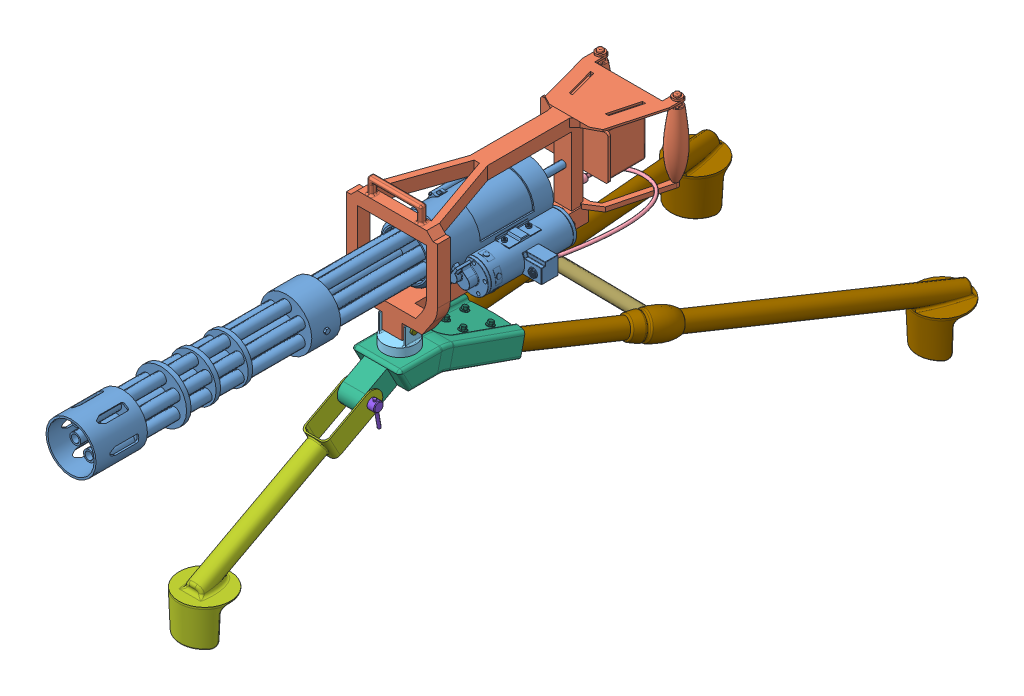
SolidWorks assembly Assembly, configuration Varsayılan. Lengths in mm.
Overall size (486.57 451.98 1218.93).
36 component instances, 16 part files, 68 mates.
Components (placement in the parent):
- MiniGun-1: MiniGun [Varsayılan] at (-74.6119 7.8433 313) size (160.38 103.95 766)
- 1-1: 1 [Varsayılan] at (-74.6119 19.0929 -136.8107) size (154.47 191.63 401.92)
- 4-1: 4 [Varsayılan] at (-65.4883 28.276 -402.319) x (-1 0 0) z (0 -0.026483 -0.999649) size (18.25 25 8)
- 5-1: 5 [Varsayılan] at (1.0631 1.0229 -8.0155) x (0.999813 -0.019344 0) z (0 0 1) size (114.19 21.33 191.94)
- 6-1: 6 [Varsayılan] at (-74.6119 -86.8456 -141.6319) size (50 96.35 50)
- 7-1: 7 [Varsayılan] at (-74.6119 -143.6696 -129.1319) x (0 0 1) z (-1 0 0) size (225.42 64.92 113.88)
- 8-1: 8 [Varsayılan] at (-74.6119 -174.7284 -49.3966) x (1 0 0) z (0 -0.470588 0.882353) size (81.78 67.4 354.56)
- 9-1: 9 [Varsayılan] at (-94.1119 -146.5519 -66.1025) x (0 0.163632 -0.986522) z (0 0.986522 0.163632) size (30 52 48)
- 10-1: 10 [Varsayılan] at (-39.5274 -147.0531 -249.291) x (-0.275637 0.214193 0.937094) z (-0.062166 -0.97679 0.204981) size (608.85 81.51 95.1)
- 10-2: 10 [Varsayılan] at (-109.6964 -147.0531 -249.291) x (0.275637 0.214193 0.937094) z (0.051454 -0.976749 0.208122) size (608.85 81.51 95.1)
- socket thin pilot cap screw_din-1: socket thin pilot cap screw_din [DIN 6912 - M4 x 10 --- 6.5N] at (-25.4764 1.646 -243) x (0 -1 0) z (-0.098825 0 0.995105) size (12.8 7 7)
- socket thin pilot cap screw_din-2: socket thin pilot cap screw_din [DIN 6912 - M4 x 10 --- 6.5N] at (-25.4764 1.6451 -281) x (0 -1 0) z (0 0 1) size (12.8 7 7)
- hexalobular socket cheese head_iso-3: hexalobular socket cheese head_iso [ISO 14580 - #4 x 5 x 3.6 - 4.8-N] at (-10.8119 -16.6334 -327) x (1 0 0) z (0 1 0) size (7 8.1 7)
- hexalobular socket cheese head_iso-5: hexalobular socket cheese head_iso [ISO 14580 - #4 x 5 x 3.6 - 4.8-N] at (-26.8628 -7.1408 -327) x (1 0 0) z (0 1 0) size (7 8.1 7)
- hexalobular socket cheese head_iso-7: hexalobular socket cheese head_iso [ISO 14580 - #4 x 5 x 3.6 - 4.8-N] at (-43.3074 -16.6352 -327) x (1 0 0) z (0 1 0) size (7 8.1 7)
- hexalobular socket cheese head_iso-9: hexalobular socket cheese head_iso [ISO 14580 - #4 x 5 x 3.6 - 4.8-N] at (-10.4181 -35.6239 -327) x (1 0 0) z (0 1 0) size (7 8.1 7)
- hexalobular socket cheese head_iso-10: hexalobular socket cheese head_iso [ISO 14580 - #4 x 5 x 3.6 - 4.8-N] at (-26.8628 -45.1182 -327) x (1 0 0) z (0 1 0) size (7 8.1 7)
- hexalobular socket cheese head_iso-11: hexalobular socket cheese head_iso [ISO 14580 - #4 x 5 x 3.6 - 4.8-N] at (-43.3074 -35.6239 -327) x (1 0 0) z (0 1 0) size (7 8.1 7)
- 11-1: 11 [Varsayılan] at (-5.6608 -84.396 1.2114) x (0.999924 -0.001016 0.012303) z (0.003781 0.97392 -0.226862) size (190.05 18 18)
- pan head cross recess screw_iso-2: pan head cross recess screw_iso [ISO 7045 - M1.6 x 5 - Z - 5N] at (16.5372 -20.1295 -280.3) x (0 0 1) z (-1 0 0) size (6.27 3.2 3.2)
- pan head cross recess screw_iso-3: pan head cross recess screw_iso [ISO 7045 - M1.6 x 5 - Z - 5N] at (6.5372 -20.1295 -280.3) x (0 0 1) z (-1 0 0) size (6.27 3.2 3.2)
- pan head cross recess screw_iso-4: pan head cross recess screw_iso [ISO 7045 - M1.6 x 5 - Z - 5N] at (16.5372 -30.1295 -280.3) x (0 0 1) z (-1 0 0) size (6.27 3.2 3.2)
- pan head cross recess screw_iso-5: pan head cross recess screw_iso [ISO 7045 - M1.6 x 5 - Z - 5N] at (6.5372 -30.1295 -280.3) x (0 0 1) z (-1 0 0) size (6.27 3.2 3.2)
- socket head cap screw_iso-2: socket head cap screw_iso [ISO 4762 M3 x 12 - 12N] at (-65.0857 13.3433 -337) x (0 0 1) z (-1 0 0) size (15 5.5 5.5)
- socket head cap screw_iso-3: socket head cap screw_iso [ISO 4762 M3 x 12 - 12N] at (-65.0857 2.3433 -337) x (0 0 1) z (-1 0 0) size (15 5.5 5.5)
- socket head cap screw_iso-4: socket head cap screw_iso [ISO 4762 M3 x 12 - 12N] at (-74.6119 -3.1567 -337) x (0 0 1) z (-1 0 0) size (15 5.5 5.5)
- socket head cap screw_iso-5: socket head cap screw_iso [ISO 4762 M3 x 12 - 12N] at (-74.6119 18.8433 -337) x (0 0 1) z (-1 0 0) size (15 5.5 5.5)
- socket head cap screw_iso-6: socket head cap screw_iso [ISO 4762 M3 x 12 - 12N] at (-84.1382 13.3433 -337) x (0 0 1) z (-1 0 0) size (15 5.5 5.5)
- socket head cap screw_iso-7: socket head cap screw_iso [ISO 4762 M3 x 12 - 12N] at (-84.1382 2.3433 -337) x (0 0 1) z (-1 0 0) size (15 5.5 5.5)
- hex flange bolt small_iso-1: hex flange bolt small_iso [ISO 4162 - M5 x 12 x 12-N] at (-61.23 -119.0865 -214.8986) x (0 -0.974859 0.222825) z (-0.222825 0.217223 0.950349) size (17.6 11.4 11.4)
- hex flange bolt small_iso-2: hex flange bolt small_iso [ISO 4162 - M5 x 12 x 12-N] at (-87.9939 -119.0865 -214.8986) x (0 -0.974859 0.222825) z (-0.222825 0.217223 0.950349) size (17.6 11.4 11.4)
- hex flange bolt small_iso-3: hex flange bolt small_iso [ISO 4162 - M5 x 12 x 12-N] at (-94.5826 -127.419 -251.3536) x (0 -0.974859 0.222825) z (-0.222825 0.217223 0.950349) size (17.6 11.4 11.4)
- hex flange bolt small_iso-4: hex flange bolt small_iso [ISO 4162 - M5 x 12 x 12-N] at (-54.6413 -127.419 -251.3536) x (0 -0.974859 0.222825) z (-0.222825 0.217223 0.950349) size (17.6 11.4 11.4)
- socket thin pilot cap screw_din-3: socket thin pilot cap screw_din [DIN 6912 - M4 x 10 --- 6.5N] at (-27.5222 -11.7662 -175.8158) x (-0.843846 0.536586 0) z (0.053028 0.083393 0.995105) size (12.8 7 7)
- socket thin pilot cap screw_din-4: socket thin pilot cap screw_din [DIN 6912 - M4 x 10 --- 6.5N] at (-39.8728 -31.189 -175.8158) x (-0.843846 0.536586 0) z (0.053028 0.083393 0.995105) size (12.8 7 7)
- 12-1: 12 [Varsayılan] at (-98.6119 -78.6696 -129.1319) size (48 15 15)
Mates (geometry in assembly coordinates):
- Çakışık1: coincident anti-aligned: plane of MiniGun-1 through (-74.6119 7.8433 -383) normal (0 0 -1); plane of 1-1 through (-60.9883 100.6283 -383) normal (0 0 1)
- Çakışık2: coincident anti-aligned: plane of MiniGun-1 through (-87.8188 -49 -166.5) normal (0 -1 0); plane of 1-1 through (-74.6119 -49 -116.8107) normal (0 1 0)
- Genişlik1: width anti-aligned: plane of MiniGun-1 through (-87.8188 -27.5086 -166.5) normal (-1 0 0); plane of MiniGun-1 through (-61.4051 -49 -166.5) normal (1 0 0); plane of 1-1 through (-58.826 -74.5262 -116.8107) normal (1 0 0); plane of 1-1 through (-90.3979 -74.5262 -116.8107) normal (-1 0 0)
- Çakışık12: coincident anti-aligned: plane of MiniGun-1 through (11.5372 -25.1295 -275.5) normal (0 0 -1); plane of 5-1 through (11.5372 -25.1295 -275.5) normal (0 0 1)
- Eş Merkezli1: concentric anti-aligned: cylinder of MiniGun-1 through (11.5372 -25.1295 -279.5) axis (0 0 1) radius 3.351; cylinder of 5-1 through (11.5372 -25.1295 -275.5) axis (0 0 -1) radius 3.3494
- Çakışık13: coincident anti-aligned: axis of 1-1 through (-90.3979 -78.6696 -129.1319) axis (1 0 0); axis of 6-1 through (-93.6119 -78.6696 -129.1319) axis (-1 0 0)
- Genişlik2: width anti-aligned: plane of 6-1 through (-55.6119 -96.6696 -116.6319) normal (-1 0 0); plane of 6-1 through (-93.6119 -96.6696 -116.6319) normal (1 0 0); plane of 1-1 through (-58.826 -74.5262 -116.8107) normal (1 0 0); plane of 1-1 through (-90.3979 -74.5262 -116.8107) normal (-1 0 0)
- Çakışık14: coincident anti-aligned: axis of 6-1 through (-74.6119 -108.6696 -129.1319) axis (0 1 0); axis of 7-1 through (-74.6119 -104.6696 -129.1319) axis (0 -1 0)
- Çakışık15: coincident anti-aligned: plane of 6-1 through (-74.6119 -103.6696 -129.1319) normal (0 -1 0); plane of 7-1 through (-74.6119 -103.6696 -129.1319) normal (0 1 0)
- Paralel1: parallel aligned: plane of 1-1 through (-74.6119 19.0929 -116.8107) normal (0 0 1); plane of 6-1 through (-74.6119 -86.8456 -116.6319) normal (0 0 1)
- Çakışık17: coincident aligned: axis of 7-1 through (-57.1119 -146.5519 -66.1025) axis (-1 0 0); axis of 8-1 through (-92.1119 -146.5519 -66.1025) axis (-1 0 0)
- Çakışık18: coincident anti-aligned: plane of 7-1 through (-57.1119 -139.5519 -43.1025) normal (1 0 0); plane of 8-1 through (-57.1119 -144.7284 -33.3966) normal (-1 0 0)
- Çakışık19: coincident aligned: axis of 7-1 through (-57.1119 -146.5519 -66.1025) axis (-1 0 0); axis of 9-1 through (-45.1119 -146.5519 -66.1025) axis (-1 0 0)
- Çakışık20: coincident anti-aligned: plane of 8-1 through (-94.1119 -144.7284 -33.3966) normal (-1 0 0); plane of 9-1 through (-94.1119 -146.5519 -66.1025) normal (1 0 0)
- Çakışık26: coincident aligned: plane of 7-1 through (-92.1119 -139.5519 -43.1025) normal (0 0.882353 0.470588); plane of 8-1 through (-74.6119 -144.7284 -33.3966) normal (0 0.882353 0.470588)
- Çakışık27: coincident anti-aligned: axis of 7-1 through (-39.5274 -147.0531 -249.291) axis (0.275637 -0.214193 -0.937094); axis of 10-1 through (4.5745 -181.324 -399.2261) axis (-0.275637 0.214193 0.937094)
- Çakışık28: coincident anti-aligned: plane of 7-1 through (-39.5274 -147.0531 -249.291) normal (0.275637 -0.214193 -0.937094); plane of 10-1 through (-39.5274 -147.0531 -249.291) normal (-0.275637 0.214193 0.937094)
- Çakışık29: coincident anti-aligned: axis of 7-1 through (-109.6964 -147.0531 -249.291) axis (-0.275637 -0.214193 -0.937094); axis of 10-2 through (-153.7984 -181.324 -399.2261) axis (0.275637 0.214193 0.937094)
- Çakışık30: coincident anti-aligned: plane of 7-1 through (-109.6964 -147.0531 -249.291) normal (-0.275637 -0.214193 -0.937094); plane of 10-2 through (-109.6964 -147.0531 -249.291) normal (0.275637 0.214193 0.937094)
- Paralel14: parallel aligned: plane of 1-1 through (-90.3979 -74.5262 -116.8107) normal (-1 0 0); plane of 7-1 through (-112.1119 -108.6696 -91.6319) normal (-1 0 0)
- Eş Merkezli3: concentric aligned: cylinder of MiniGun-1 through (-25.4764 -9.1549 -243) axis (0 1 0) radius 2; cylinder of socket thin pilot cap screw_din-1 through (-25.4764 33.396 -243) axis (0 1 0) radius 3.5
- Eş Merkezli4: concentric aligned: cylinder of MiniGun-1 through (-25.4764 -9.1549 -281) axis (0 1 0) radius 2; cylinder of socket thin pilot cap screw_din-2 through (-25.4764 33.3951 -281) axis (0 1 0) radius 3.5
- Çakışık32: coincident anti-aligned: plane of MiniGun-1 through (-29.6119 -1.1549 -237) normal (0 1 0); plane of socket thin pilot cap screw_din-2 through (-21.9764 -1.1549 -281) normal (0 -1 0)
- Çakışık34: coincident anti-aligned: plane of MiniGun-1 through (-26.8628 -26.1295 -332) normal (0 0 -1); plane of hexalobular socket cheese head_iso-3 through (-8.7419 -16.6334 -332) normal (0 0 1)
- Eş Merkezli101: concentric aligned: cylinder of MiniGun-1 through (-26.8628 -7.1408 -327) axis (0 0 -1) radius 2.75; cone of hexalobular socket cheese head_iso-5 through (-26.8628 -7.1408 -332) axis (0 0 -1)
- Çakışık361: coincident anti-aligned: plane of MiniGun-1 through (-26.8628 -26.1295 -332) normal (0 0 -1); plane of hexalobular socket cheese head_iso-5 through (-24.7928 -7.1408 -332) normal (0 0 1)
- Eş Merkezli121: concentric aligned: cylinder of MiniGun-1 through (-43.3074 -16.6352 -327) axis (0 0 -1) radius 2.75; cone of hexalobular socket cheese head_iso-7 through (-43.3074 -16.6352 -332) axis (0 0 -1)
- Çakışık381: coincident anti-aligned: plane of MiniGun-1 through (-26.8628 -26.1295 -332) normal (0 0 -1); plane of hexalobular socket cheese head_iso-7 through (-41.2374 -16.6352 -332) normal (0 0 1)
- Eş Merkezli141: concentric aligned: cylinder of MiniGun-1 through (-10.4181 -35.6239 -327) axis (0 0 -1) radius 2.75; cone of hexalobular socket cheese head_iso-9 through (-10.4181 -35.6239 -332) axis (0 0 -1)
- Çakışık401: coincident anti-aligned: plane of MiniGun-1 through (-26.8628 -26.1295 -332) normal (0 0 -1); plane of hexalobular socket cheese head_iso-9 through (-8.3481 -35.6239 -332) normal (0 0 1)
- Eş Merkezli151: concentric aligned: cylinder of MiniGun-1 through (-26.8628 -45.1182 -327) axis (0 0 -1) radius 2.75; cone of hexalobular socket cheese head_iso-10 through (-26.8628 -45.1182 -332) axis (0 0 -1)
- Çakışık411: coincident anti-aligned: plane of MiniGun-1 through (-26.8628 -26.1295 -332) normal (0 0 -1); plane of hexalobular socket cheese head_iso-10 through (-24.7928 -45.1182 -332) normal (0 0 1)
- Eş Merkezli161: concentric aligned: cylinder of MiniGun-1 through (-43.3074 -35.6239 -327) axis (0 0 -1) radius 2.75; cone of hexalobular socket cheese head_iso-11 through (-43.3074 -35.6239 -332) axis (0 0 -1)
- Çakışık421: coincident anti-aligned: plane of MiniGun-1 through (-26.8628 -26.1295 -332) normal (0 0 -1); plane of hexalobular socket cheese head_iso-11 through (-41.2374 -35.6239 -332) normal (0 0 1)
- Eş Merkezli164: concentric aligned: cylinder of MiniGun-1 through (16.5372 -20.1295 -277) axis (0 0 -1) radius 0.4; cylinder of pan head cross recess screw_iso-2 through (16.5372 -20.1295 -305.7) axis (0 0 -1) radius 1.6
- Çakışık425: coincident anti-aligned: plane of MiniGun-1 through (-74.6119 7.8433 -279) normal (0 0 -1); plane of pan head cross recess screw_iso-2 through (16.5372 -19.3295 -279) normal (0 0 1)
- Eş Merkezli165: concentric aligned: cylinder of MiniGun-1 through (6.5372 -20.1295 -277) axis (0 0 -1) radius 0.4; cylinder of pan head cross recess screw_iso-3 through (6.5372 -20.1295 -305.7) axis (0 0 -1) radius 1.6
- Çakışık426: coincident anti-aligned: plane of MiniGun-1 through (-74.6119 7.8433 -279) normal (0 0 -1); plane of pan head cross recess screw_iso-3 through (6.5372 -19.3295 -279) normal (0 0 1)
- Eş Merkezli166: concentric aligned: cylinder of MiniGun-1 through (16.5372 -30.1295 -277) axis (0 0 -1) radius 0.4; cylinder of pan head cross recess screw_iso-4 through (16.5372 -30.1295 -305.7) axis (0 0 -1) radius 1.6
- Çakışık427: coincident anti-aligned: plane of MiniGun-1 through (-74.6119 7.8433 -279) normal (0 0 -1); plane of pan head cross recess screw_iso-4 through (16.5372 -29.3295 -279) normal (0 0 1)
- Eş Merkezli167: concentric aligned: cylinder of MiniGun-1 through (6.5372 -30.1295 -277) axis (0 0 -1) radius 0.4; cylinder of pan head cross recess screw_iso-5 through (6.5372 -30.1295 -305.7) axis (0 0 -1) radius 1.6
- Çakışık428: coincident anti-aligned: plane of MiniGun-1 through (-74.6119 7.8433 -279) normal (0 0 -1); plane of pan head cross recess screw_iso-5 through (6.5372 -29.3295 -279) normal (0 0 1)
- Eş Merkezli169: concentric aligned: cylinder of MiniGun-1 through (-65.0857 13.3433 -321.3431) axis (0 0 -1) radius 2; cylinder of socket head cap screw_iso-2 through (-65.0857 13.3433 -368.75) axis (0 0 -1) radius 2.75
- Çakışık429: coincident anti-aligned: plane of MiniGun-1 through (-74.6119 7.8433 -334) normal (0 0 -1); plane of socket head cap screw_iso-2 through (-65.0857 16.0933 -334) normal (0 0 1)
- Eş Merkezli170: concentric aligned: cylinder of MiniGun-1 through (-65.0857 2.3433 -321.3431) axis (0 0 -1) radius 2; cylinder of socket head cap screw_iso-3 through (-65.0857 2.3433 -368.75) axis (0 0 -1) radius 2.75
- Çakışık430: coincident anti-aligned: plane of MiniGun-1 through (-74.6119 7.8433 -334) normal (0 0 -1); plane of socket head cap screw_iso-3 through (-65.0857 5.0933 -334) normal (0 0 1)
- Eş Merkezli171: concentric aligned: cylinder of MiniGun-1 through (-74.6119 -3.1567 -321.3431) axis (0 0 -1) radius 2; cylinder of socket head cap screw_iso-4 through (-74.6119 -3.1567 -368.75) axis (0 0 -1) radius 2.75
- Çakışık431: coincident anti-aligned: plane of MiniGun-1 through (-74.6119 7.8433 -334) normal (0 0 -1); plane of socket head cap screw_iso-4 through (-74.6119 -0.4067 -334) normal (0 0 1)
- Eş Merkezli172: concentric aligned: cylinder of MiniGun-1 through (-74.6119 18.8433 -321.3431) axis (0 0 -1) radius 2; cylinder of socket head cap screw_iso-5 through (-74.6119 18.8433 -368.75) axis (0 0 -1) radius 2.75
- Çakışık432: coincident anti-aligned: plane of MiniGun-1 through (-74.6119 7.8433 -334) normal (0 0 -1); plane of socket head cap screw_iso-5 through (-74.6119 21.5933 -334) normal (0 0 1)
- Eş Merkezli173: concentric aligned: cylinder of MiniGun-1 through (-84.1382 13.3433 -321.3431) axis (0 0 -1) radius 2; cylinder of socket head cap screw_iso-6 through (-84.1382 13.3433 -368.75) axis (0 0 -1) radius 2.75
- Çakışık433: coincident anti-aligned: plane of MiniGun-1 through (-74.6119 7.8433 -334) normal (0 0 -1); plane of socket head cap screw_iso-6 through (-84.1382 16.0933 -334) normal (0 0 1)
- Eş Merkezli174: concentric aligned: cylinder of MiniGun-1 through (-84.1382 2.3433 -321.3431) axis (0 0 -1) radius 2; cylinder of socket head cap screw_iso-7 through (-84.1382 2.3433 -368.75) axis (0 0 -1) radius 2.75
- Çakışık434: coincident anti-aligned: plane of MiniGun-1 through (-74.6119 7.8433 -334) normal (0 0 -1); plane of socket head cap screw_iso-7 through (-84.1382 5.0933 -334) normal (0 0 1)
- Eş Merkezli175: concentric aligned: cylinder of 7-1 through (-61.23 -186.9366 -199.39) axis (0 0.974859 -0.222825) radius 3.5; cylinder of hex flange bolt small_iso-1 through (-61.23 -119.0865 -214.8986) axis (0 0.974859 -0.222825) radius 2.5
- Çakışık435: coincident anti-aligned: plane of 7-1 through (-74.6119 -121.6975 -201.1898) normal (0 0.974859 -0.222825); plane of hex flange bolt small_iso-1 through (-57.2901 -124.345 -212.7729) normal (0 -0.974859 0.222825)
- Eş Merkezli176: concentric aligned: cylinder of 7-1 through (-87.9939 -186.9366 -199.39) axis (0 0.974859 -0.222825) radius 3.5; cylinder of hex flange bolt small_iso-2 through (-87.9939 -119.0865 -214.8986) axis (0 0.974859 -0.222825) radius 2.5
- Çakışık436: coincident anti-aligned: plane of 7-1 through (-74.6119 -121.6975 -201.1898) normal (0 0.974859 -0.222825); plane of hex flange bolt small_iso-2 through (-84.0541 -124.345 -212.7729) normal (0 -0.974859 0.222825)
- Eş Merkezli177: concentric aligned: cylinder of 7-1 through (-94.5826 -195.2692 -235.845) axis (0 0.974859 -0.222825) radius 3.5; cylinder of hex flange bolt small_iso-3 through (-94.5826 -127.419 -251.3536) axis (0 0.974859 -0.222825) radius 2.5
- Çakışık437: coincident anti-aligned: plane of 7-1 through (-74.6119 -121.6975 -201.1898) normal (0 0.974859 -0.222825); plane of hex flange bolt small_iso-3 through (-90.6428 -132.6776 -249.2278) normal (0 -0.974859 0.222825)
- Eş Merkezli178: concentric aligned: cylinder of 7-1 through (-54.6413 -195.2692 -235.845) axis (0 0.974859 -0.222825) radius 3.5; cylinder of hex flange bolt small_iso-4 through (-54.6413 -127.419 -251.3536) axis (0 0.974859 -0.222825) radius 2.5
- Çakışık438: coincident anti-aligned: plane of 7-1 through (-74.6119 -121.6975 -201.1898) normal (0 0.974859 -0.222825); plane of hex flange bolt small_iso-4 through (-50.7014 -132.6776 -249.2278) normal (0 -0.974859 0.222825)
- Eş Merkezli18221: concentric aligned: cylinder of MiniGun-1 through (-36.6357 -5.9711 -175.8158) axis (0.843846 -0.536586 0) radius 2.1942; cylinder of socket thin pilot cap screw_din-3 through (-0.7301 -28.8028 -175.8158) axis (0.843846 -0.536586 0) radius 3.5
- Çakışık44221: coincident anti-aligned: plane of MiniGun-1 through (-27.7807 -6.9545 -193.9) normal (0.843846 -0.536586 0); plane of socket thin pilot cap screw_din-3 through (-31.7538 -13.2028 -175.47) normal (-0.843846 0.536586 0)
- Eş Merkezli18231: concentric aligned: cylinder of MiniGun-1 through (-48.9863 -25.3939 -175.8158) axis (0.843846 -0.536586 0) radius 2.1942; cylinder of socket thin pilot cap screw_din-4 through (-13.0807 -48.2256 -175.8158) axis (0.843846 -0.536586 0) radius 3.5
- Çakışık44231: coincident anti-aligned: plane of MiniGun-1 through (-27.7807 -6.9545 -193.9) normal (0.843846 -0.536586 0); plane of socket thin pilot cap screw_din-4 through (-44.1044 -32.6255 -175.47) normal (-0.843846 0.536586 0)
- Çakışık4424: coincident aligned: axis of 6-1 through (-53.6119 -78.6696 -129.1319) axis (-1 0 0); axis of 12-1 through (-50.6119 -78.6696 -129.1319) axis (-1 0 0)
- Çakışık4425: coincident anti-aligned: plane of 6-1 through (-95.6119 -98.6696 -116.6319) normal (-1 0 0); plane of 12-1 through (-95.6119 -78.6696 -129.1319) normal (1 0 0)
